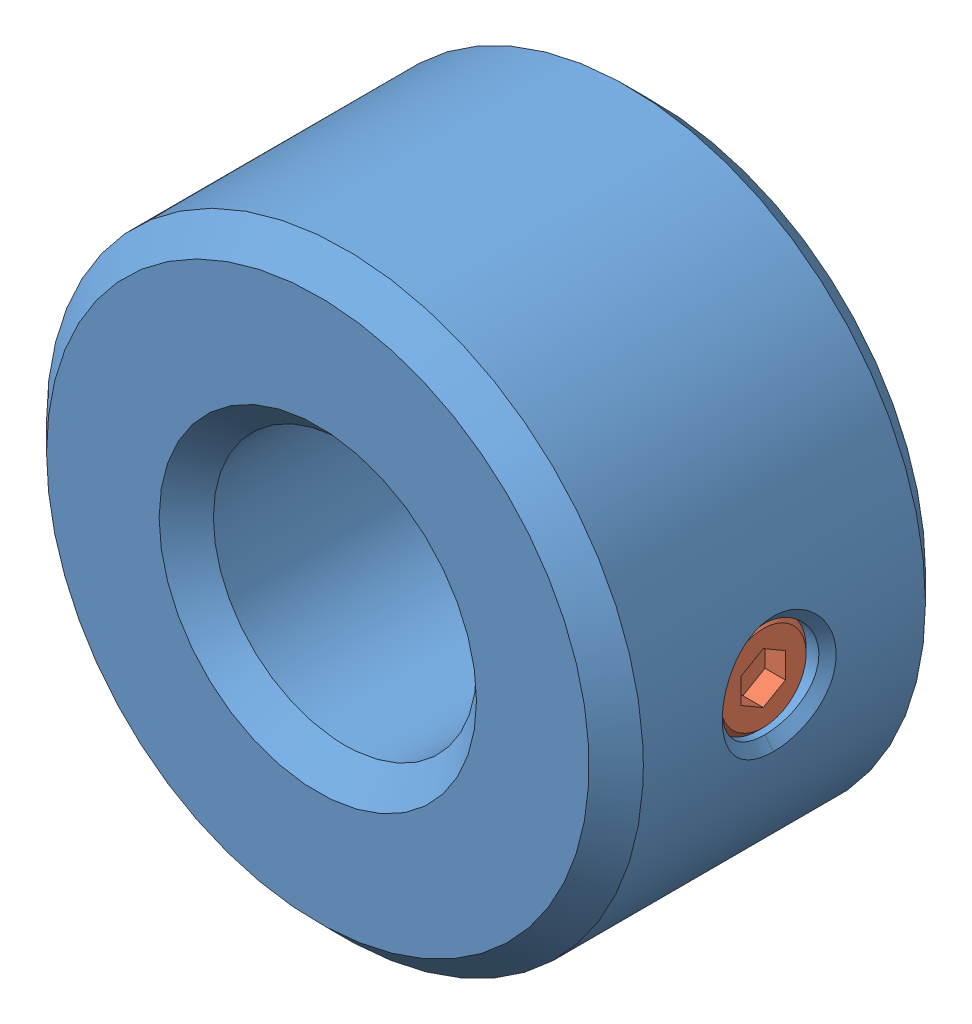
SolidWorks assembly Tetrix Axle Collar, configuration Default. Lengths in mm.
Overall size (11 11 6.2).
2 component instances, 2 part files, 0 mates.
Components (placement in the parent):
- Tetrix Axle Collar Body-1: Tetrix Axle Collar Body [Default] at origin size (11 11 6.2)
- Tetrix Axle Collar Set Screw-1: Tetrix Axle Collar Set Screw [Default] at (5.2058 0 0.0953) x (0 1 0) z (0 0 1) size (1.78 2.95 1.78)
